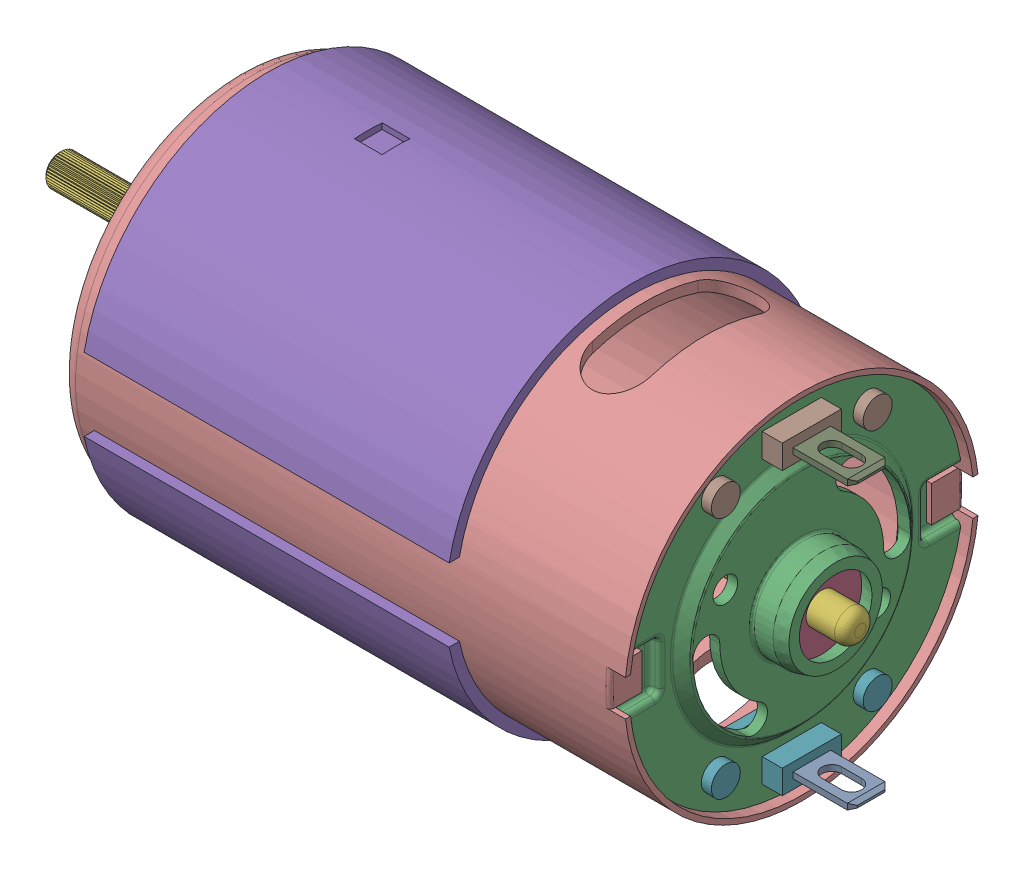
SolidWorks assembly CCL-9015-am-0912, configuration Default. Lengths in mm.
Overall size (82.02 37.83 37.47).
10 component instances, 8 part files, 0 mates.
Components (placement in the parent):
- AM-0912 terminal-1: AM-0912 terminal [Default] at (29.27 -13.055 -1.5854) size (10.06 0.6 3.8)
- AM-0912 output bushing-1: AM-0912 output bushing [Default] at (-28.166 1.123 -1.5904) size (4.5 10.97 10.97)
- AM-0912 end cap-1: AM-0912 end cap [Default] at (24.952 1.123 -1.5904) size (6.48 34.65 34.46)
- AM-0912 cap bushing-1: AM-0912 cap bushing [Default] at (31.302 1.123 -1.5904) size (3.04 8.08 8.08)
- AM-0912 shield-1: AM-0912 shield [Default] at (-21.634 1.123 -1.5904) x (1 0 0) z (0 -1 0) size (36.88 37.47 37.83)
- AM-0912 shaft-1: AM-0912 shaft [Default] at (-32.682 1.123 -1.5904) x (1 0 0) z (0 0.970706 0.240271) size (80.92 3.36 3.32)
- AM-0912 terminal housing-1: AM-0912 terminal housing [Default] at (30.286 -13.101 -1.5904) x (-1 0 0) z (0 0 1) size (4.06 4.83 19.05)
- AM-0912 terminal housing-2: AM-0912 terminal housing [Default] at (30.286 15.347 -1.5904) x (-1 0 0) z (0 0 -1) size (4.06 4.83 19.05)
- AM-0912 terminal-2: AM-0912 terminal [Default] at (29.27 15.301 -1.5954) size (10.06 0.6 3.8)
- AM-0912 housing-1: AM-0912 housing [Default] at (32.318 1.123 -1.5904) size (61.5 35.8 35.8)
